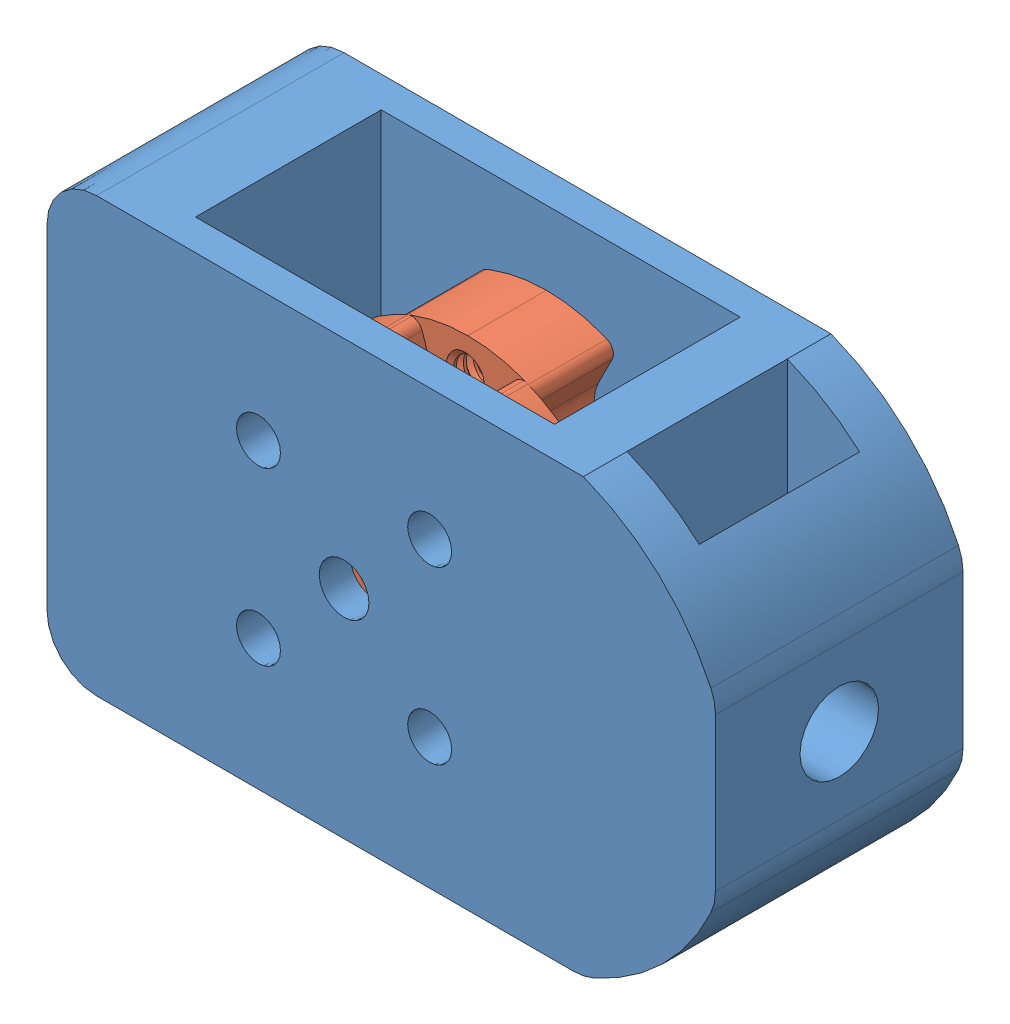
SolidWorks assembly ARMUS-103-200, configuration Défaut. Lengths in mm.
Overall size (54 35 20).
3 component instances, 3 part files, 9 mates.
Components (placement in the parent):
- ARMUS-REV4-201-1: ARMUS-REV4-201 [Défaut] at origin size (54 35 20)
- HUB-0_25-1: HUB-0_25 [Défaut] at (-30.0172 37.5992 -6.2696) x (-1 0 0) z (0 -1 0) size (25.4 12.7 25.4)
- hex nut_ai-2: hex nut_ai [HNUT 0.2500-20-D-N] at (19.3798 17.5 0) x (0 0.5 0.866025) z (-1 0 0) size (11.11 12.83 5.74)
Mates (geometry in assembly coordinates):
- Coïncidente1: coordinate: point of ARMUS-REV2-003-1
- Largeur2: width anti-aligned: plane of ARMUS-REV2-003-1 through (14.5 0 7.5) normal (0 0 -1); plane of HUB-0_25-1 through (14.5 0 -7.5) normal (0 0 1); plane of ARMUS-REV2-003-1 through (0 17.5 6.35) normal (0 0 1); plane of HUB-0_25-1 through (0 17.5 -6.35) normal (0 0 -1)
- Largeur3: width aligned: plane of ARMUS-REV2-003-1 through (0 35 0) normal (0 1 0); plane of HNUT 0.2500-20-D-N-1 through (0 0 0) normal (0 -1 0); plane of ARMUS-REV2-003-1 through (25.1202 23.0562 3.2079) normal (0 1 0); plane of HNUT 0.2500-20-D-N-1 through (25.1202 11.9437 -3.2079) normal (0 -1 0)
- Largeur4: width: cylinder of ARMUS-REV2-003-1; plane of HNUT 0.2500-20-D-N-1 through (30 35 10) normal (0 0 1); cylinder of ARMUS-REV2-003-1 through (25.1202 17.5 0) axis (-1 0 0) radius 2.5527
- Largeur5: width aligned: plane of ARMUS-REV2-003-1 through (14.5 0 7.5) normal (-1 0 0); plane of HNUT 0.2500-20-D-N-1 through (30 35 10) normal (1 0 0); plane of ARMUS-REV2-003-1 through (19.3798 23.0562 -3.2079) normal (-1 0 0); plane of HNUT 0.2500-20-D-N-1 through (25.1202 23.0562 -3.2079) normal (1 0 0)
- Largeur6: width aligned: plane of ARMUS-REV2-003-1 through (14.5 0 -7.5) normal (0 0 1); plane of ARMUS-REV2-003-1 through (14.5 0 7.5) normal (0 0 -1); plane of HUB-0_25-1 through (0 17.5 6.35) normal (0 0 1); plane of HUB-0_25-1 through (0 17.5 -6.35) normal (0 0 -1)
- Largeur7: width: plane of ARMUS-REV2-003-1 through (14.5 0 7.5) normal (-1 0 0); plane of ARMUS-REV2-003-1 through (-14.5 0 7.5) normal (1 0 0); cylinder of HUB-0_25-1 through (0 17.5 1.5875) axis (0 0 1) radius 3.175
- Parallèle1: parallel anti-aligned: plane of HUB-0_25-1 through (-30.0172 37.5992 -6.2696) normal (-1 0 0)
- Largeur8: width: plane of ARMUS-REV2-003-1 through (0 0 0) normal (0 -1 0); plane of HUB-0_25-1 through (0 35 0) normal (0 1 0); cylinder of ARMUS-REV2-003-1 through (0 17.5 1.5875) axis (0 0 1) radius 3.175
